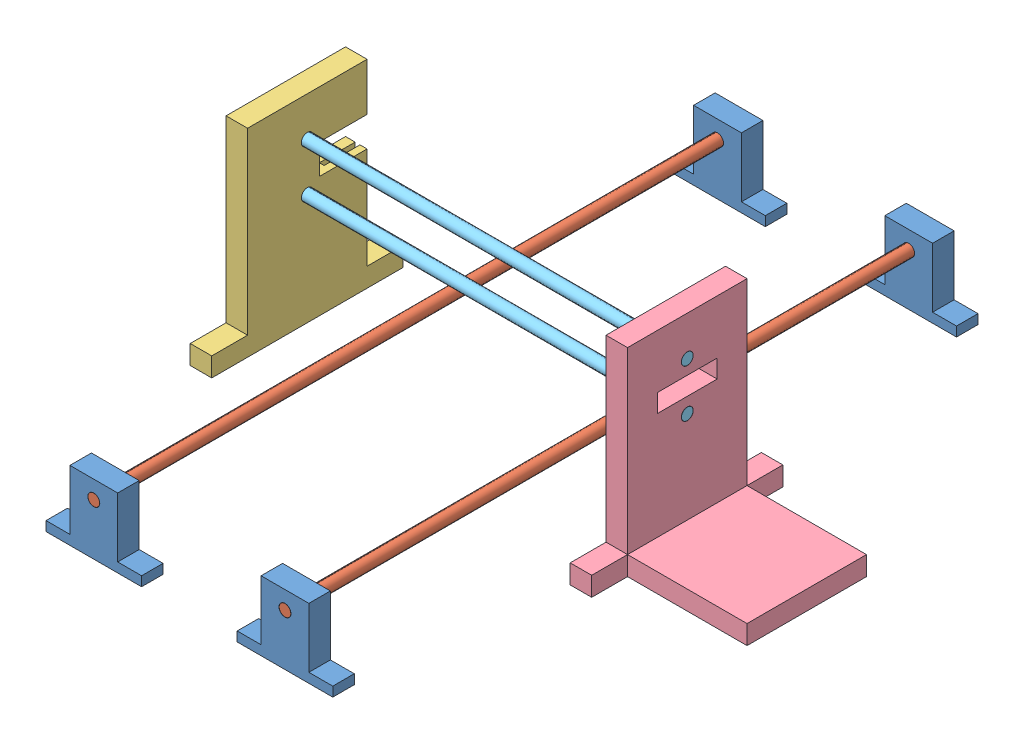
SolidWorks assembly Y axes components, configuration Défaut. Lengths in mm.
Overall size (218 83 270).
10 component instances, 5 part files, 17 mates.
Components (placement in the parent):
- Pièce1-6: Pièce1 [Défaut] at (49.2725 -7.8577 44.5) size (40 29 9)
- Pièce1-8: Pièce1 [Défaut] at (129.2725 -7.8577 44.5) size (40 29 9)
- Pièce1-9: Pièce1 [Défaut] at (129.2725 -7.8577 305.5) size (40 29 9)
- Pièce1-10: Pièce1 [Défaut] at (49.2725 -7.8577 305.5) size (40 29 9)
- barre de guidage-3: barre de guidage [Défaut] at (69.2725 13.6423 35.5) size (4.9 4.9 270)
- barre de guidage-5: barre de guidage [Défaut] at (-10.7275 13.6423 35.5) size (4.9 4.9 270)
- X pièce for pulley-4: X pièce for pulley [Défaut] at (-51.7275 -7.8577 216.7066) x (0 0 -1) z (1 0 0) size (80 83 9)
- X pièce-1: X pièce [Défaut] at (107.2725 -7.8577 216.7066) x (0 0 -1) z (1 0 0) size (80 83 59)
- barre de guidage X axes-1: barre de guidage X axes [Défaut] at (-60.7275 58.6423 175.1534) x (0 0 -1) z (1 0 0) size (4.9 4.9 168)
- barre de guidage X axes-2: barre de guidage X axes [Défaut] at (107.2725 38.6423 175.1534) x (0 0 1) z (-1 0 0) size (4.9 4.9 168)
Mates (geometry in assembly coordinates):
- Coïncidente7: coincident aligned: line of Pièce1-6 through (9.2725 -7.8577 44.5) axis (-1 0 0); line of Pièce1-8 through (89.2725 -7.8577 44.5) axis (-1 0 0)
- Distance2: distance = 40 mm: point of Pièce1-6; point of Pièce1-8
- Coïncidente9: coincident aligned: line of Pièce1-8 through (89.2725 -7.8577 35.5) axis (0 0 1); line of Pièce1-9 through (89.2725 -7.8577 296.5) axis (0 0 1)
- Coïncidente10: coincident aligned: line of Pièce1-6 through (-30.7275 -7.8577 35.5) axis (0 0 1); line of Pièce1-10 through (-30.7275 -7.8577 296.5) axis (0 0 1)
- Coaxiale1: concentric aligned: circle of Pièce1-9; circle of barre de guidage-3
- Coïncidente15: coincident aligned: plane of Pièce1-8 through (129.2725 -7.8577 35.5) normal (0 0 -1); plane of barre de guidage-3 through (69.2725 13.6423 35.5) normal (0 0 -1)
- Coïncidente19: coincident aligned: plane of Pièce1-9 through (129.2725 -7.8577 305.5) normal (0 0 1); plane of barre de guidage-3 through (69.2725 13.6423 305.5) normal (0 0 1)
- Coïncidente24: coincident aligned: plane of Pièce1-6 through (49.2725 -7.8577 35.5) normal (0 0 -1); plane of barre de guidage-5 through (-10.7275 13.6423 35.5) normal (0 0 -1)
- Coaxiale4: concentric aligned: circle of Pièce1-6; circle of barre de guidage-5
- Coïncidente25: coincident aligned: plane of Pièce1-10 through (49.2725 -7.8577 305.5) normal (0 0 1); plane of barre de guidage-5 through (-10.7275 13.6423 305.5) normal (0 0 1)
- Distance5: distance = 150 mm: line of X pièce-1 through (98.2725 -7.8577 215.1534) axis (0 0 -1); line of X pièce for pulley-4 through (-51.7275 -7.8577 215.1534) axis (0 0 -1)
- Distance26: distance = 30 mm: line of X pièce for pulley-4 through (-60.7275 -7.8577 215.1534) axis (0 0 -1); line of Pièce1-10 through (-30.7275 -7.8577 296.5) axis (0 0 1)
- Parallèle9: parallel anti-aligned: line of Pièce1-9 through (89.2725 -7.8577 296.5) axis (0 0 1); line of X pièce-1 through (107.2725 -7.8577 215.1534) axis (0 0 -1)
- Coaxiale5: concentric aligned: circle of X pièce for pulley-4; circle of barre de guidage X axes-1
- Coïncidente67: coincident aligned: plane of X pièce-1 through (107.2725 -7.8577 216.7066) normal (1 0 0); plane of barre de guidage X axes-1 through (107.2725 58.6423 175.1534) normal (1 0 0)
- Coaxiale6: concentric anti-aligned: circle of X pièce for pulley-4; circle of barre de guidage X axes-2
- Coïncidente68: coincident aligned: plane of X pièce for pulley-4 through (-60.7275 -7.8577 216.7066) normal (-1 0 0); plane of barre de guidage X axes-2 through (-60.7275 38.6423 175.1534) normal (-1 0 0)
